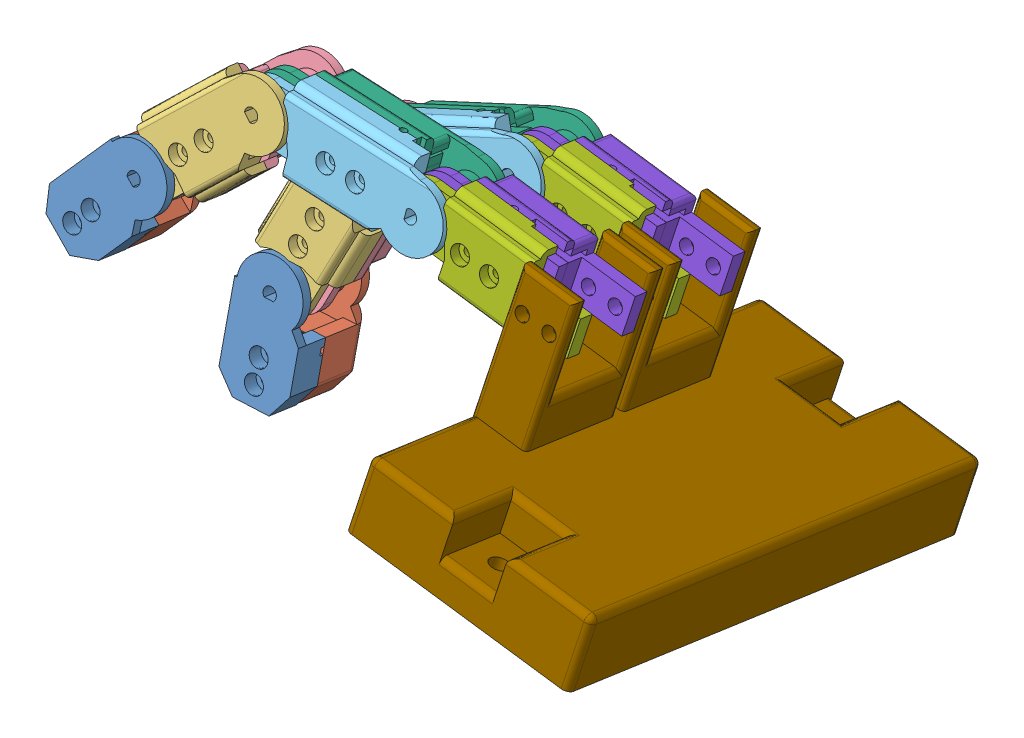
SolidWorks assembly assem_finger_base, configuration Default. Lengths in mm.
Overall size (153.62 83.36 109.33).
17 component instances, 9 part files, 42 mates.
Components (placement in the parent):
- v3_digital_phalanx_left-1: v3_digital_phalanx_left [Default] at (43.1107 -30.8045 31.2213) x (0.63554 0.743276 -0.208879) z (0.078088 0.207275 0.975161) size (27.7 15 7)
- v3_digital_phalanx_right-1: v3_digital_phalanx_right [Default] at (41.9393 -33.9136 16.5939) x (0.63554 0.743276 -0.208879) z (0.078088 0.207275 0.975161) size (27.7 15 10)
- v3_medial_plalanx_left-1: v3_medial_plalanx_left [Default] at (64.4935 -9.973 27.4398) x (-0.706701 -0.678422 0.200792) z (-0.078088 -0.207275 -0.975161) size (42.66 17.5 7)
- v3_medial_plalanx_right-1: v3_medial_plalanx_right [Default] at (41.965 -33.8493 16.8858) x (0.706701 0.678422 -0.200792) z (0.078088 0.207275 0.975161) size (42.66 17.5 10)
- v3_proxiaml_plalanx_left-1: v3_proxiaml_plalanx_left [Default] at (99.2608 -13.6734 25.7499) x (-0.992583 0.107582 0.056616) z (-0.078088 -0.207275 -0.975161) size (47.66 17.5 7)
- v3_proxiaml_plalanx_right-1: v3_proxiaml_plalanx_right [Default] at (63.1929 -13.4317 11.1538) x (0.992583 -0.107582 -0.056616) z (0.078088 0.207275 0.975161) size (47.66 17.5 10)
- v3_mcp_holder_left-1: v3_mcp_holder_left [Default] at (128.7672 -19.0414 24.8358) x (-0.982663 0.180987 0.040219) z (-0.078088 -0.207275 -0.975161) size (42.71 17.5 7)
- v3_mcp_holder_right-1: v3_mcp_holder_right [Default] at (97.9598 -17.1355 9.4646) x (0.982663 -0.180987 -0.040219) z (0.078088 0.207275 0.975161) size (42.71 17.5 10.1)
- v3_base_2-1: v3_base_2 [Default] at (140.6041 -62.605 11.5614) x (0.078088 0.207275 0.975161) z (-0.982663 0.180987 0.040219) size (100 45 50)
- v3_proxiaml_plalanx_right-2: v3_proxiaml_plalanx_right [Default] at (63.5854 -34.6103 -10.1154) x (0.925368 0.348875 -0.148256) z (0.078088 0.207275 0.975161) size (47.66 17.5 10)
- v3_proxiaml_plalanx_left-2: v3_proxiaml_plalanx_left [Default] at (97.3007 -18.876 1.2734) x (-0.925368 -0.348875 0.148256) z (-0.078088 -0.207275 -0.975161) size (47.66 17.5 7)
- v3_mcp_holder_left-2: v3_mcp_holder_left [Default] at (126.8072 -24.244 0.3592) x (-0.982663 0.180987 0.040219) z (-0.078088 -0.207275 -0.975161) size (42.71 17.5 7)
- v3_medial_plalanx_left-2: v3_medial_plalanx_left [Default] at (64.8877 -31.1528 6.1708) x (-0.367016 -0.903476 0.221428) z (-0.078088 -0.207275 -0.975161) size (42.66 17.5 7)
- v3_mcp_holder_right-2: v3_mcp_holder_right [Default] at (95.9998 -22.3381 -15.0119) x (0.982663 -0.180987 -0.040219) z (0.078088 0.207275 0.975161) size (42.71 17.5 10.1)
- v3_medial_plalanx_right-2: v3_medial_plalanx_right [Default] at (52.5497 -61.7807 -3.7641) x (0.367016 0.903476 -0.221428) z (0.078088 0.207275 0.975161) size (42.66 17.5 10)
- v3_digital_phalanx_right-2: v3_digital_phalanx_right [Default] at (52.5251 -61.8458 -4.056) x (0.008193 0.977982 -0.208531) z (0.078088 0.207275 0.975161) size (27.7 15 10)
- v3_digital_phalanx_left-2: v3_digital_phalanx_left [Default] at (53.6964 -58.7366 10.5714) x (0.008193 0.977982 -0.208531) z (0.078088 0.207275 0.975161) size (27.7 15 7)
Mates (geometry in assembly coordinates):
- Coincident1: coincident anti-aligned: plane of v3_digital_phalanx_left-1 through (42.7202 -31.8409 26.3455) normal (-0.078088 -0.207275 -0.975161); plane of v3_digital_phalanx_right-1 through (42.7202 -31.8409 26.3455) normal (0.078088 0.207275 0.975161)
- Concentric1: concentric anti-aligned: cylinder of v3_digital_phalanx_left-1 through (32.7314 -42.5954 37.6351) axis (-0.078088 -0.207275 -0.975161) radius 0.95; cylinder of v3_digital_phalanx_right-1 through (31.482 -45.9118 22.0325) axis (0.078088 0.207275 0.975161) radius 0.95
- Concentric2: concentric anti-aligned: cylinder of v3_digital_phalanx_left-1 through (35.9091 -38.879 36.5907) axis (-0.078088 -0.207275 -0.975161) radius 0.95; cylinder of v3_digital_phalanx_right-1 through (34.6597 -42.1954 20.9881) axis (0.078088 0.207275 0.975161) radius 0.95
- Coincident2: coincident anti-aligned: plane of v3_medial_plalanx_left-1 through (51.0943 -28.1393 25.1958) normal (-0.078088 -0.207275 -0.975161); plane of v3_medial_plalanx_right-1 through (45.4623 -24.7919 24.9353) normal (0.078088 0.207275 0.975161)
- Concentric3: concentric anti-aligned: cylinder of v3_medial_plalanx_left-1 through (56.1068 -17.8653 31.0195) axis (-0.078088 -0.207275 -0.975161) radius 0.95; cylinder of v3_medial_plalanx_right-1 through (54.6856 -21.6377 13.2716) axis (0.078088 0.207275 0.975161) radius 0.95
- Concentric4: concentric anti-aligned: cylinder of v3_medial_plalanx_left-1 through (51.5133 -22.275 32.3247) axis (-0.078088 -0.207275 -0.975161) radius 0.95; cylinder of v3_medial_plalanx_right-1 through (50.092 -26.0474 14.5767) axis (0.078088 0.207275 0.975161) radius 0.95
- Coincident9: coincident anti-aligned: plane of v3_digital_phalanx_left-1 through (43.017 -31.0532 30.0511) normal (-0.078088 -0.207275 -0.975161); plane of v3_medial_plalanx_left-1 through (43.017 -31.0532 30.0511) normal (0.078088 0.207275 0.975161)
- Concentric6: concentric aligned: cylinder of v3_digital_phalanx_left-1 through (43.4074 -30.0168 34.9269) axis (-0.078088 -0.207275 -0.975161) radius 1.4; cylinder of v3_medial_plalanx_left-1 through (43.095 -30.8459 31.0263) axis (-0.078088 -0.207275 -0.975161) radius 3
- Coincident10: coincident anti-aligned: plane of v3_proxiaml_plalanx_left-1 through (74.2562 -15.5875 20.9808) normal (-0.078088 -0.207275 -0.975161); plane of v3_proxiaml_plalanx_right-1 through (71.2174 -9.0278 19.8298) normal (0.078088 0.207275 0.975161)
- Concentric10: concentric anti-aligned: cylinder of v3_proxiaml_plalanx_left-1 through (80.9917 -11.4344 27.9675) axis (-0.078088 -0.207275 -0.975161) radius 0.95; cylinder of v3_proxiaml_plalanx_right-1 through (79.5705 -15.2068 10.2196) axis (0.078088 0.207275 0.975161) radius 0.95
- Concentric11: concentric anti-aligned: cylinder of v3_proxiaml_plalanx_left-1 through (87.4435 -12.1337 27.5995) axis (-0.078088 -0.207275 -0.975161) radius 0.95; cylinder of v3_proxiaml_plalanx_right-1 through (86.0223 -15.9061 9.8516) axis (0.078088 0.207275 0.975161) radius 0.95
- Coincident12: coincident anti-aligned: plane of v3_medial_plalanx_left-1 through (64.2436 -10.6362 24.3193) normal (-0.078088 -0.207275 -0.975161); plane of v3_proxiaml_plalanx_left-1 through (64.2436 -10.6362 24.3193) normal (0.078088 0.207275 0.975161)
- Concentric12: concentric aligned: cylinder of v3_medial_plalanx_left-1 through (64.4935 -9.973 27.4398) axis (-0.078088 -0.207275 -0.975161) radius 1.4; cylinder of v3_proxiaml_plalanx_left-1 through (64.3217 -10.429 25.2945) axis (-0.078088 -0.207275 -0.975161) radius 3
- Coincident13: coincident anti-aligned: plane of v3_mcp_holder_left-1 through (106.714 -19.6792 19.559) normal (-0.078088 -0.207275 -0.975161); plane of v3_mcp_holder_right-1 through (106.1527 -13.2801 18.2438) normal (0.078088 0.207275 0.975161)
- Concentric13: concentric anti-aligned: cylinder of v3_mcp_holder_left-1 through (117.0689 -16.6208 26.4886) axis (-0.078088 -0.207275 -0.975161) radius 0.95; cylinder of v3_mcp_holder_right-1 through (115.6477 -20.3932 8.7407) axis (0.078088 0.207275 0.975161) radius 0.95
- Concentric14: concentric anti-aligned: cylinder of v3_mcp_holder_left-1 through (110.6816 -15.4444 26.75) axis (-0.078088 -0.207275 -0.975161) radius 0.95; cylinder of v3_mcp_holder_right-1 through (109.2604 -19.2168 9.0021) axis (0.078088 0.207275 0.975161) radius 0.95
- Coincident15: coincident anti-aligned: plane of v3_proxiaml_plalanx_left-1 through (99.0109 -14.3367 22.6294) normal (-0.078088 -0.207275 -0.975161); plane of v3_mcp_holder_left-1 through (99.0109 -14.3367 22.6294) normal (0.078088 0.207275 0.975161)
- Concentric16: concentric aligned: cylinder of v3_proxiaml_plalanx_left-1 through (99.2608 -13.6734 25.7499) axis (-0.078088 -0.207275 -0.975161) radius 1.4; cylinder of v3_mcp_holder_left-1 through (99.089 -14.1294 23.6046) axis (-0.078088 -0.207275 -0.975161) radius 3
- Coincident16: coincident anti-aligned: plane of v3_mcp_holder_left-1 through (99.2873 -13.6118 26.0424) normal (0.078088 0.207275 0.975161); plane of v3_base_2-1 through (137.0402 -12.6262 22.8097) normal (-0.078088 -0.207275 -0.975161)
- Concentric17: concentric anti-aligned: cylinder of v3_mcp_holder_left-1 through (131.8099 -22.2617 12.971) axis (0.078088 0.207275 0.975161) radius 1.5; cylinder of v3_base_2-1 through (135.0076 -13.7738 52.9038) axis (-0.078088 -0.207275 -0.975161) radius 1.5
- Concentric18: concentric anti-aligned: cylinder of v3_mcp_holder_left-1 through (125.9139 -21.1758 13.2123) axis (0.078088 0.207275 0.975161) radius 1.5; cylinder of v3_base_2-1 through (129.1116 -12.6879 53.1451) axis (-0.078088 -0.207275 -0.975161) radius 1.5
- Coincident17: coincident anti-aligned: plane of v3_medial_plalanx_left-2 through (59.4481 -53.0769 4.0881) normal (-0.078088 -0.207275 -0.975161); plane of v3_medial_plalanx_right-2 through (52.9595 -52.1936 4.42) normal (0.078088 0.207275 0.975161)
- Concentric19: concentric anti-aligned: cylinder of v3_medial_plalanx_left-2 through (58.1916 -47.6184 11.4374) axis (-0.078088 -0.207275 -0.975161) radius 0.95; cylinder of v3_medial_plalanx_right-2 through (56.7704 -51.3908 -6.3106) axis (0.078088 0.207275 0.975161) radius 0.95
- Concentric20: concentric aligned: cylinder of v3_medial_plalanx_left-2 through (53.6808 -58.7781 10.3764) axis (-0.078088 -0.207275 -0.975161) radius 3; cylinder of v3_digital_phalanx_left-2 through (53.9932 -57.949 14.277) axis (-0.078088 -0.207275 -0.975161) radius 1.4
- Coincident18: coincident anti-aligned: plane of v3_digital_phalanx_right-2 through (53.306 -59.773 5.6956) normal (0.078088 0.207275 0.975161); plane of v3_digital_phalanx_left-2 through (53.306 -59.773 5.6956) normal (-0.078088 -0.207275 -0.975161)
- Concentric21: concentric anti-aligned: cylinder of v3_digital_phalanx_right-2 through (52.5445 -77.7635 1.3768) axis (0.078088 0.207275 0.975161) radius 0.95; cylinder of v3_digital_phalanx_left-2 through (53.7939 -74.4471 16.9794) axis (-0.078088 -0.207275 -0.975161) radius 0.95
- Concentric22: concentric anti-aligned: cylinder of v3_proxiaml_plalanx_right-2 through (78.8539 -28.8539 -12.5616) axis (0.078088 0.207275 0.975161) radius 0.95; cylinder of v3_proxiaml_plalanx_left-2 through (80.2751 -25.0815 5.1863) axis (-0.078088 -0.207275 -0.975161) radius 0.95
- Coincident19: coincident anti-aligned: plane of v3_proxiaml_plalanx_left-2 through (64.6378 -31.8161 3.0503) normal (0.078088 0.207275 0.975161); plane of v3_medial_plalanx_left-2 through (64.6378 -31.8161 3.0503) normal (-0.078088 -0.207275 -0.975161)
- Coincident20: coincident anti-aligned: plane of v3_mcp_holder_left-2 through (104.754 -24.8818 -4.9176) normal (-0.078088 -0.207275 -0.975161); plane of v3_mcp_holder_right-2 through (104.1927 -18.4827 -6.2328) normal (0.078088 0.207275 0.975161)
- Concentric23: concentric anti-aligned: cylinder of v3_proxiaml_plalanx_right-2 through (84.8688 -26.5862 -13.5253) axis (0.078088 0.207275 0.975161) radius 0.95; cylinder of v3_proxiaml_plalanx_left-2 through (86.29 -22.8138 4.2227) axis (-0.078088 -0.207275 -0.975161) radius 0.95
- Concentric24: concentric anti-aligned: cylinder of v3_digital_phalanx_right-2 through (52.5854 -72.8736 0.3341) axis (0.078088 0.207275 0.975161) radius 0.95; cylinder of v3_digital_phalanx_left-2 through (53.8349 -69.5572 15.9367) axis (-0.078088 -0.207275 -0.975161) radius 0.95
- Concentric25: concentric aligned: cylinder of v3_proxiaml_plalanx_left-2 through (64.7159 -31.6088 4.0254) axis (-0.078088 -0.207275 -0.975161) radius 3; cylinder of v3_medial_plalanx_left-2 through (64.8877 -31.1528 6.1708) axis (-0.078088 -0.207275 -0.975161) radius 1.4
- Concentric26: concentric anti-aligned: cylinder of v3_medial_plalanx_left-2 through (60.5772 -41.7458 9.9981) axis (-0.078088 -0.207275 -0.975161) radius 0.95; cylinder of v3_medial_plalanx_right-2 through (59.156 -45.5182 -7.7498) axis (0.078088 0.207275 0.975161) radius 0.95
- Coincident21: coincident anti-aligned: plane of v3_proxiaml_plalanx_right-2 through (69.6672 -27.1963 -1.9236) normal (0.078088 0.207275 0.975161); plane of v3_proxiaml_plalanx_left-2 through (75.4035 -31.7166 -1.4221) normal (-0.078088 -0.207275 -0.975161)
- Concentric27: concentric anti-aligned: cylinder of v3_mcp_holder_left-2 through (115.1089 -21.8234 2.0121) axis (-0.078088 -0.207275 -0.975161) radius 0.95; cylinder of v3_mcp_holder_right-2 through (113.6877 -25.5958 -15.7359) axis (0.078088 0.207275 0.975161) radius 0.95
- Coincident22: coincident anti-aligned: plane of v3_proxiaml_plalanx_left-2 through (97.0509 -19.5393 -1.8471) normal (-0.078088 -0.207275 -0.975161); plane of v3_mcp_holder_left-2 through (97.0509 -19.5393 -1.8471) normal (0.078088 0.207275 0.975161)
- Concentric28: concentric anti-aligned: cylinder of v3_mcp_holder_left-2 through (108.7216 -20.647 2.2735) axis (-0.078088 -0.207275 -0.975161) radius 0.95; cylinder of v3_mcp_holder_right-2 through (107.3004 -24.4194 -15.4745) axis (0.078088 0.207275 0.975161) radius 0.95
- Coincident23: coincident anti-aligned: plane of v3_medial_plalanx_left-2 through (53.6027 -58.9854 9.4012) normal (0.078088 0.207275 0.975161); plane of v3_digital_phalanx_left-2 through (53.6027 -58.9854 9.4012) normal (-0.078088 -0.207275 -0.975161)
- Concentric29: concentric aligned: cylinder of v3_proxiaml_plalanx_left-2 through (97.3007 -18.876 1.2734) axis (-0.078088 -0.207275 -0.975161) radius 1.4; cylinder of v3_mcp_holder_left-2 through (97.129 -19.332 -0.872) axis (-0.078088 -0.207275 -0.975161) radius 3
- Concentric30: concentric aligned: cylinder of v3_base_2-1 through (127.1988 -34.5013 -44.6123) axis (0.078088 0.207275 0.975161) radius 1.5; cylinder of v3_mcp_holder_left-2 through (129.8499 -27.4643 -11.5056) axis (0.078088 0.207275 0.975161) radius 1.5
- Concentric31: concentric anti-aligned: cylinder of v3_base_2-1 through (121.3028 -33.4154 -44.371) axis (0.078088 0.207275 0.975161) radius 1.5; cylinder of v3_mcp_holder_right-2 through (124.5008 -24.9275 -4.4382) axis (-0.078088 -0.207275 -0.975161) radius 1.5
- Coincident24: coincident anti-aligned: plane of v3_base_2-1 through (133.7527 -21.3525 -18.2446) normal (0.078088 0.207275 0.975161); plane of v3_mcp_holder_right-2 through (95.9998 -22.3381 -15.0119) normal (-0.078088 -0.207275 -0.975161)
